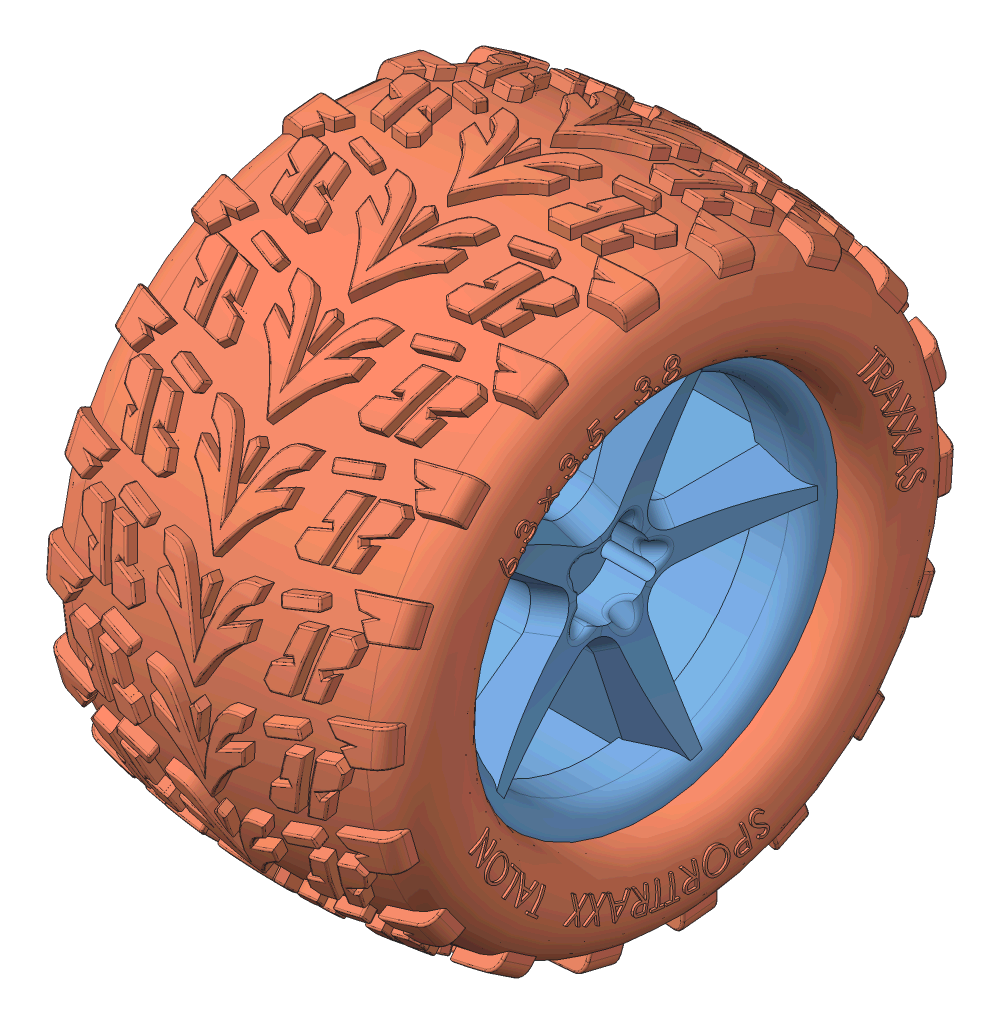
SolidWorks assembly Wheel, configuration Default. Lengths in mm.
Overall size (106.88 166.05 166.47).
2 component instances, 2 part files, 4 mates.
Components (placement in the parent):
- Wheel Rim-1: Wheel Rim [Default] at (-5.7009 0 0) size (78.74 101.6 101.6)
- Wheel Tire-1: Wheel Tire [Default] at (-5.7009 -0.0005 -0.0001) size (106.88 166.05 166.47)
Mates (geometry in assembly coordinates):
- Concentric1: concentric aligned: cylinder of Wheel Rim-1 through (-45.0709 0 0) axis (-1 0 0) radius 50.8; cylinder of Wheel Tire-1 through (-45.0732 0 0) axis (-1 0 0) radius 50.8
- Coincident1: coincident aligned: plane of Wheel Rim-1 through (-5.7009 0 0) normal (1 0 0); plane of Wheel Tire-1 through (-5.7009 -0.0005 -0.0001) normal (1 0 0)
- Coincident2: coincident aligned: plane of Wheel Rim-1 through (-5.7009 0 0) normal (0 0 1); plane of assembly through (0 0 0) normal (0 0 1)
- Coincident3: coincident aligned: plane of Wheel Rim-1 through (-5.7009 0 0) normal (0 1 0); plane of assembly through (0 0 0) normal (0 1 0)
